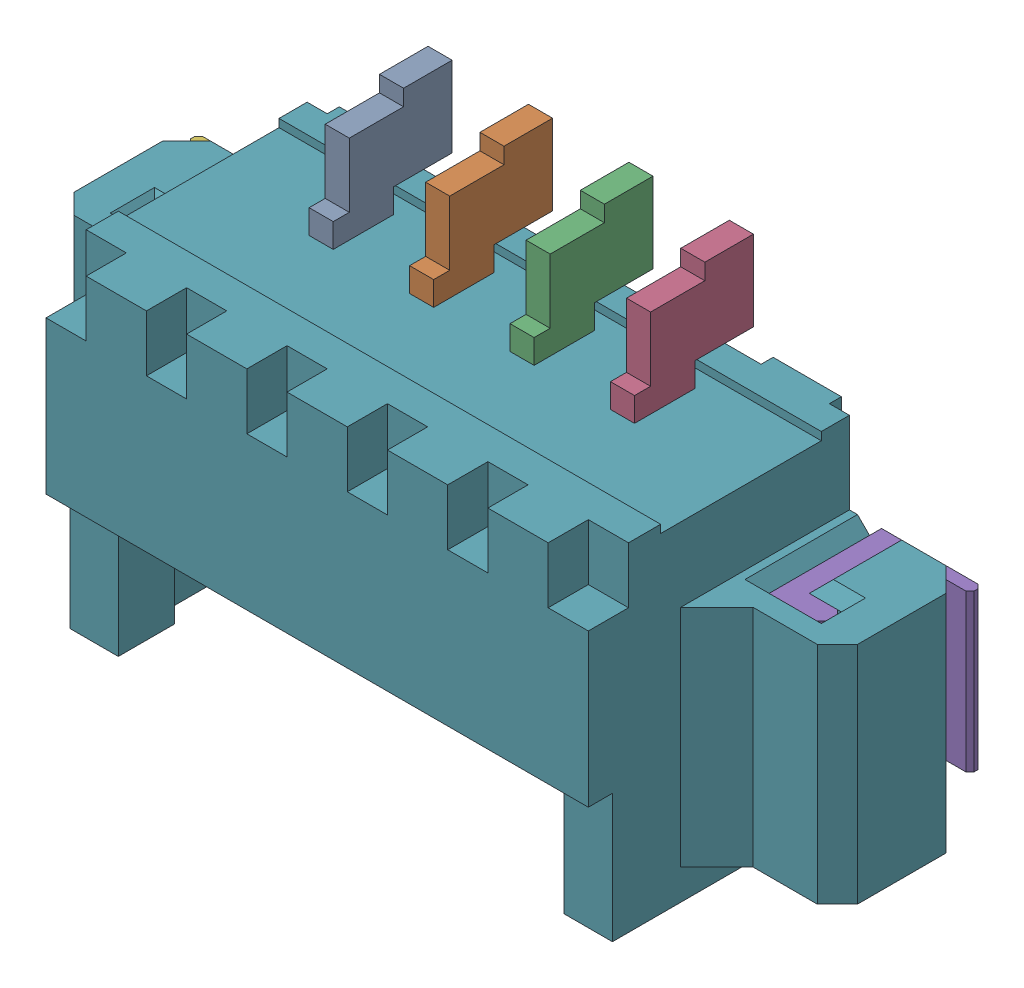
SolidWorks assembly 653104131822, configuration Default. Lengths in mm.
Overall size (9.75 5.4 3.41).
7 component instances, 3 part files, 0 mates.
Components (placement in the parent):
- 6531xx131822_PIN_2-1: 6531xx131822_PIN_2 [Default] at (-1.875 2.7 -0.425) x (1 0 0) z (0 -1 0) size (0.3 1.48 4.54)
- 6531xx131822_PIN_2-2: 6531xx131822_PIN_2 [Default] at (-0.625 2.7 -0.425) x (1 0 0) z (0 -1 0) size (0.3 1.48 4.54)
- 6531xx131822_PIN_2-3: 6531xx131822_PIN_2 [Default] at (0.625 2.7 -0.425) x (1 0 0) z (0 -1 0) size (0.3 1.48 4.54)
- 6531xx131822_PIN_2-4: 6531xx131822_PIN_2 [Default] at (1.875 2.7 -0.425) x (1 0 0) z (0 -1 0) size (0.3 1.48 4.54)
- 6531xx131822_PIN_FLANGE_2-1: 6531xx131822_PIN_FLANGE_2 [Default] at (3.75 -0.045 -1.05) size (1.25 1.95 1.4)
- 6531xx131822_PIN_FLANGE_2-2: 6531xx131822_PIN_FLANGE_2 [Default] at (-3.75 -0.045 -1.05) x (-1 0 0) z (0 0 1) size (1.25 1.95 1.4)
- 653104131822-1: 653104131822 [Default] at origin size (9.75 4.2 3.4)
